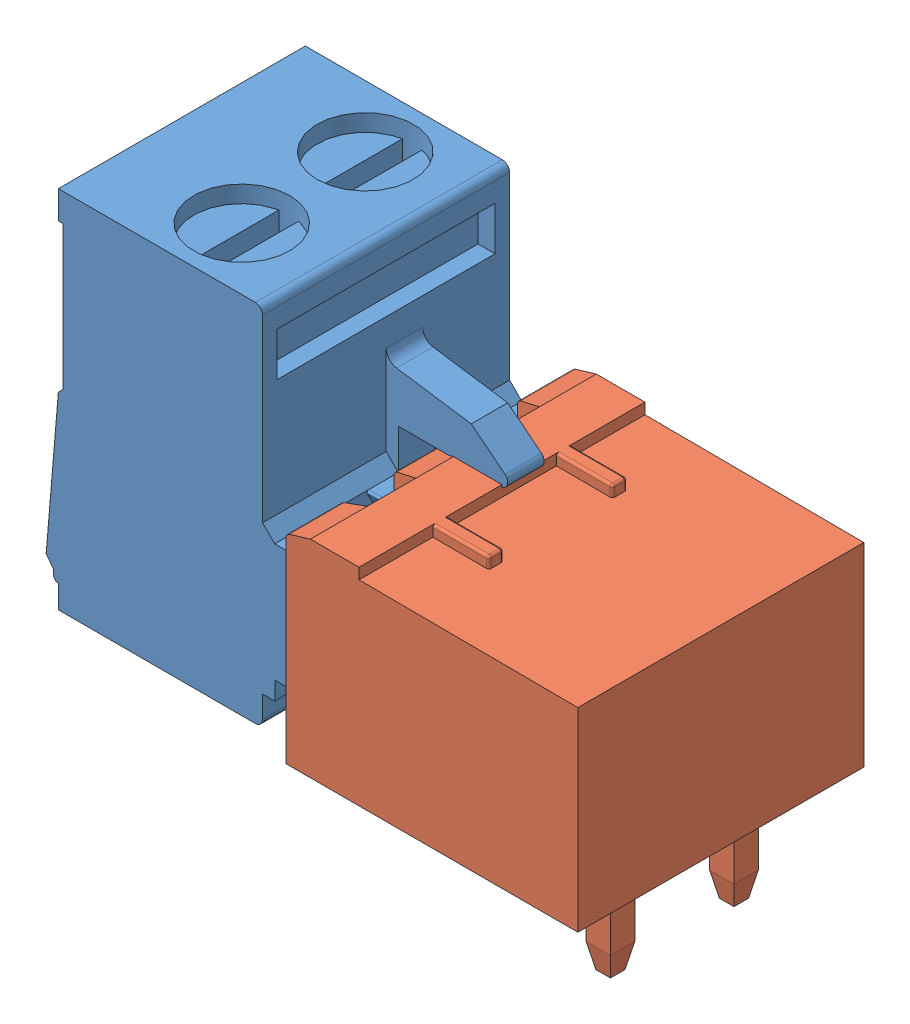
SolidWorks assembly Assem1, configuration Default. Lengths in mm.
Overall size (22.66 19 11.76).
2 component instances, 2 part files, 2 mates.
Components (placement in the parent):
- CUI_DEVICES_TBP01P1-508-02BE-1: CUI_DEVICES_TBP01P1-508-02BE [Default] at (-6.8076 5.0819 11.7651) size (18 15 10.16)
- CUI_DEVICES_TBP01R1-508-02BE-1: CUI_DEVICES_TBP01R1-508-02BE [Default] at (-5.5431 5.0819 11.7651) size (12 12.5 11.76)
Mates (geometry in assembly coordinates):
- Concentric1: concentric anti-aligned: circle of CUI_DEVICES_TBP01P1-508-02BE-1; circle of CUI_DEVICES_TBP01R1-508-02BE-1
- Parallel1: parallel anti-aligned: line of CUI_DEVICES_TBP01P1-508-02BE-1 through (10.6924 7.2319 9.2251) axis (0 1 0); line of CUI_DEVICES_TBP01R1-508-02BE-1 through (3.3569 12.5116 8.9251) axis (0 -1 0)
